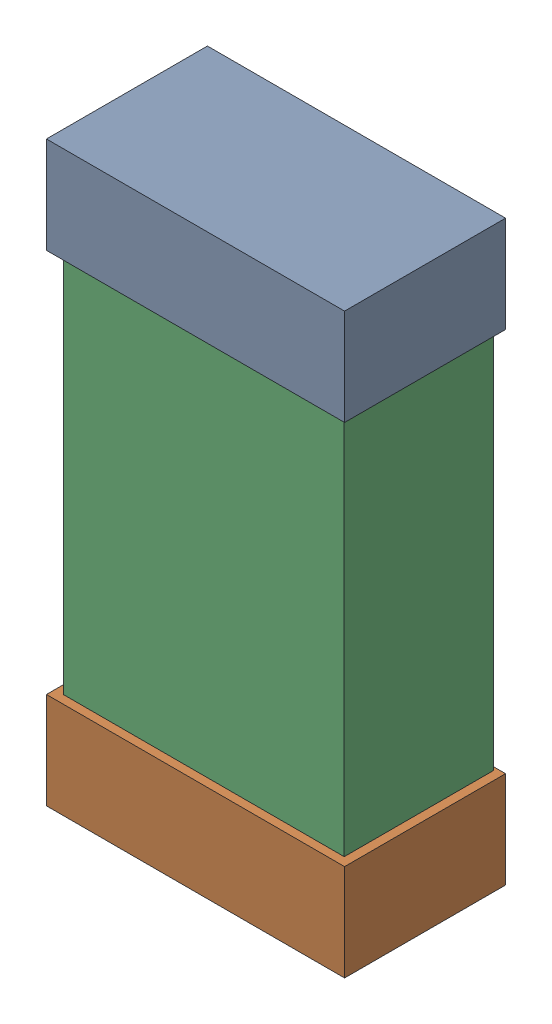
SolidWorks assembly R42, configuration Default. Lengths in mm.
Overall size (0.85 1.65 0.46).
6 component instances, 2 part files, 0 mates.
Components (placement in the parent):
- 432138512_20-1: 432138512_20 [Default] at (45.1501 5.1291 -0.8715) size (0.85 0.28 0.46)
  - Extruded-1: Extruded [Default] at origin size (0.85 0.28 0.46)
- 432138512_21-1: 432138512_21 [Default] at (45.1501 3.7576 -0.8715) size (0.85 0.28 0.46)
  - Extruded-1: Extruded [Default] at origin size (0.85 0.28 0.46)
- 432124816_10-1: 432124816_10 [Default] at (45.1501 4.4434 -0.8615) size (0.8 1.5 0.42)
  - Extruded (1)-1: Extruded (1) [Default] at origin size (0.8 1.5 0.42)
